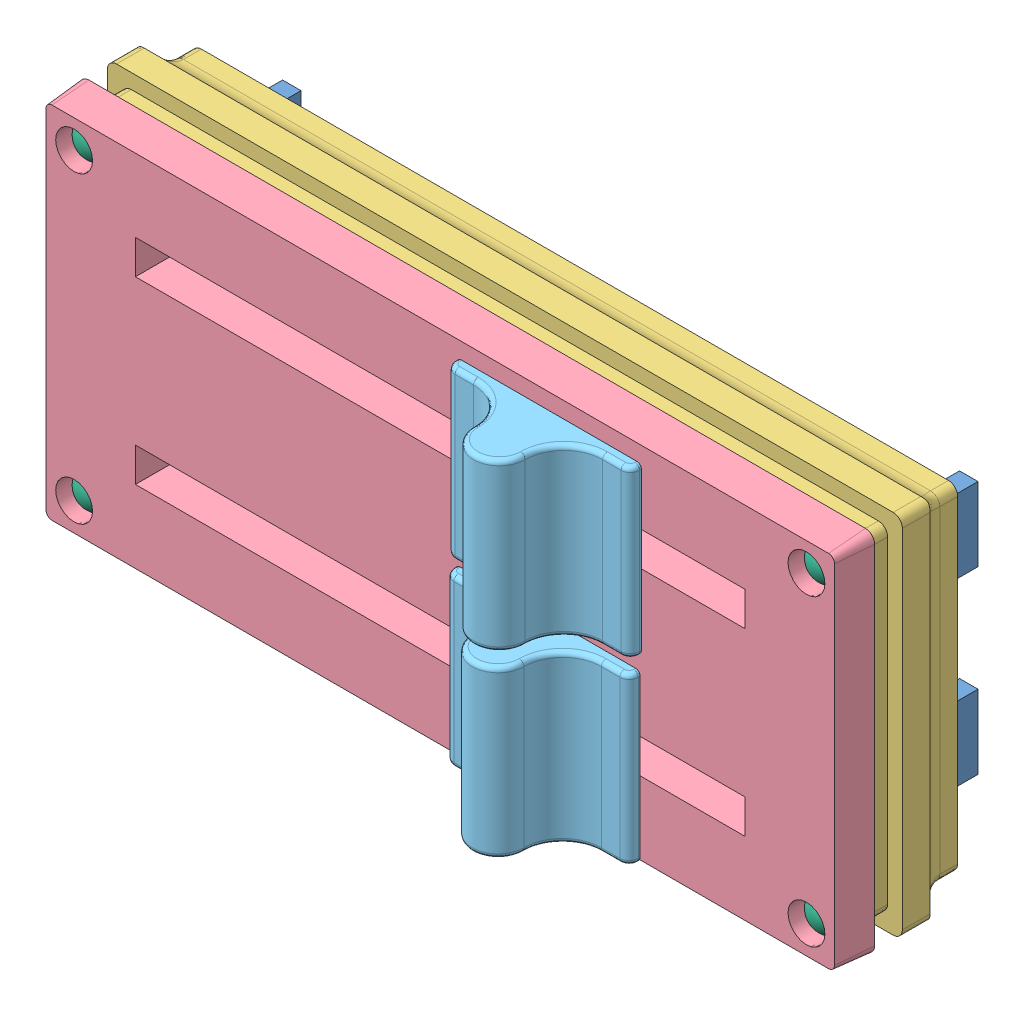
SolidWorks assembly SliderAssem, configuration По умолчанию. Lengths in mm.
Overall size (86.2 39.7 29.8).
14 component instances, 6 part files, 22 mates.
Components (placement in the parent):
- B10K SC6080GH-1: B10K SC6080GH [По умолчанию] at origin size (75.4 9.4 27)
- B10K SC6080GH-2: B10K SC6080GH [По умолчанию] at (0 19.5 0) size (75.4 9.4 27)
- M2x4 screw-2: M2x4 screw [По умолчанию] at (-35.5 19.5 8.6) x (0.943582 0.33114 0) z (0.33114 -0.943582 0) size (3.5 5.75 3.5)
- SliderBase-1: SliderBase [По умолчанию] at origin size (86.2 39.7 9.6)
- SliderTop-1: SliderTop [По умолчанию] at origin size (86.2 39.7 4)
- Knob-1: Knob [По умолчанию] at origin size (20 18 8.2)
- Knob-2: Knob [По умолчанию] at (0.1323 19.5 0) size (20 18 8.2)
- M2x4 screw-3: M2x4 screw [По умолчанию] at (35.5 19.5 8.6) x (0.879143 0.476558 0) z (0.476558 -0.879143 0) size (3.5 5.75 3.5)
- M2x4 screw-4: M2x4 screw [По умолчанию] at (35.5 0 8.6) x (0.811306 0.584622 0) z (0.584622 -0.811306 0) size (3.5 5.75 3.5)
- M2x4 screw-5: M2x4 screw [По умолчанию] at (-35.5 0 8.6) x (0.753279 0.657701 0) z (0.657701 -0.753279 0) size (3.5 5.75 3.5)
- M2x10selftapping-1: M2x10selftapping [Default] at (39.7 -6.7 13.6) x (0.603612 0.797278 0) z (0.797278 -0.603612 0) size (3.4 11.3 3.4)
- M2x10selftapping-2: M2x10selftapping [Default] at (39.7 26.2 13.6) x (0.469566 0.882898 0) z (0.882898 -0.469566 0) size (3.4 11.3 3.4)
- M2x10selftapping-3: M2x10selftapping [Default] at (-39.7 -6.7 13.6) x (0.353322 0.935502 0) z (0.935502 -0.353322 0) size (3.4 11.3 3.4)
- M2x10selftapping-4: M2x10selftapping [Default] at (-39.7 26.2 13.6) x (0.264584 0.964363 0) z (0.964363 -0.264584 0) size (3.4 11.3 3.4)
Mates (geometry in assembly coordinates):
- Coincident2: coincident aligned: plane of Slider-1 through (0 0 7) normal (0 0 1); plane of Slider-2 through (0 19.5 7) normal (0 0 1)
- Coincident3: coincident aligned: plane of Slider-1 through (37.7 4.7 7) normal (1 0 0); plane of Slider-2 through (37.7 24.2 7) normal (1 0 0)
- Distance2: distance = 18 mm: cylinder of Slider-1 through (35.5 0 2) axis (0 0 1) radius 0.75; cylinder of Slider-2 through (35.5 19.5 2) axis (0 0 1) radius 0.75
- Concentric3: concentric anti-aligned: cylinder of Slider-2 through (-35.5 19.5 2) axis (0 0 1) radius 0.75; cylinder of screw1-2 through (-35.5 19.5 3.9973) axis (0 0 -1) radius 1
- Distance4: distance = 1.6 mm anti-aligned: plane of Slider-2 through (0 19.5 7) normal (0 0 1); plane of screw1-2 through (-36.4436 19.1689 8.6) normal (0 0 -1)
- Coincident4: coincident anti-aligned: plane of Slider-2 through (10.6693 20.1 22) normal (0 0 1); plane of knob1-2 through (10.8016 20.1 22) normal (0 0 -1)
- Width2: width anti-aligned: plane of knob1-2 through (14.1016 18.7 26.6819) normal (0 1 0); plane of knob1-2 through (14.1016 20.3 26.6819) normal (0 -1 0); plane of Slider-2 through (0 18.9 0) normal (0 -1 0); plane of Slider-2 through (0 20.1 0) normal (0 1 0)
- Width3: width anti-aligned: plane of Slider-2 through (32.7 21 2) normal (-1 0 0); plane of Slider-2 through (-32.7 21 2) normal (1 0 0); plane of knob1-2 through (10.6016 20.3 26.6819) normal (1 0 0); plane of knob1-2 through (15.0016 20.3 26.6819) normal (-1 0 0)
- Concentric4: concentric anti-aligned: cylinder of Slider-2 through (35.5 19.5 2) axis (0 0 1) radius 0.75; cylinder of screw M2x4-3 through (35.5 19.5 3.9973) axis (0 0 -1) radius 1
- Distance5: distance = 1.6 mm anti-aligned: plane of Slider-2 through (0 19.5 7) normal (0 0 1); plane of screw M2x4-3 through (34.6209 19.0234 8.6) normal (0 0 -1)
- Distance6: distance = 1.6 mm anti-aligned: plane of Slider-2 through (0 19.5 7) normal (0 0 1); plane of screw M2x4-4 through (34.6887 -0.5846 8.6) normal (0 0 -1)
- Concentric5: concentric anti-aligned: cylinder of Slider-1 through (35.5 0 2) axis (0 0 1) radius 0.75; cylinder of screw M2x4-4 through (35.5 0 3.9973) axis (0 0 -1) radius 1
- Distance7: distance = 1.6 mm anti-aligned: plane of Slider-2 through (0 19.5 7) normal (0 0 1); plane of screw M2x4-5 through (-36.2533 -0.6577 8.6) normal (0 0 -1)
- Concentric6: concentric anti-aligned: cylinder of Slider-1 through (-35.5 0 2) axis (0 0 1) radius 0.75; cylinder of screw M2x4-5 through (-35.5 0 3.9973) axis (0 0 -1) radius 1
- Concentric7: concentric aligned: cylinder of BaseholderPart2-1 through (39.7 -6.7 1) axis (0 0 1) radius 0.85; cylinder of M2x10selftaping-1 through (39.7 -6.7 13.6) axis (0 0 1) radius 1
- Coincident5: coincident anti-aligned: plane of TopfasePart1-1 through (39.7 -6.7 13.6) normal (0 0 1); plane of M2x10selftaping-1 through (39.0964 -7.4973 13.6) normal (0 0 -1)
- Concentric8: concentric aligned: cylinder of BaseholderPart2-1 through (39.7 26.2 1) axis (0 0 1) radius 0.85; cylinder of M2x10selftaping-2 through (39.7 26.2 13.6) axis (0 0 1) radius 1
- Coincident6: coincident anti-aligned: plane of TopfasePart1-1 through (39.7 -6.7 13.6) normal (0 0 1); plane of M2x10selftaping-2 through (39.2304 25.3171 13.6) normal (0 0 -1)
- Coincident7: coincident anti-aligned: plane of TopfasePart1-1 through (39.7 -6.7 13.6) normal (0 0 1); plane of M2x10selftaping-3 through (-40.0533 -7.6355 13.6) normal (0 0 -1)
- Concentric9: concentric aligned: cylinder of BaseholderPart2-1 through (-39.7 -6.7 1) axis (0 0 1) radius 0.85; cylinder of M2x10selftaping-3 through (-39.7 -6.7 13.6) axis (0 0 1) radius 1
- Coincident8: coincident anti-aligned: plane of TopfasePart1-1 through (39.7 -6.7 13.6) normal (0 0 1); plane of M2x10selftaping-4 through (-39.9646 25.2356 13.6) normal (0 0 -1)
- Concentric10: concentric aligned: cylinder of BaseholderPart2-1 through (-39.7 26.2 1) axis (0 0 1) radius 0.85; cylinder of M2x10selftaping-4 through (-39.7 26.2 13.6) axis (0 0 1) radius 1
